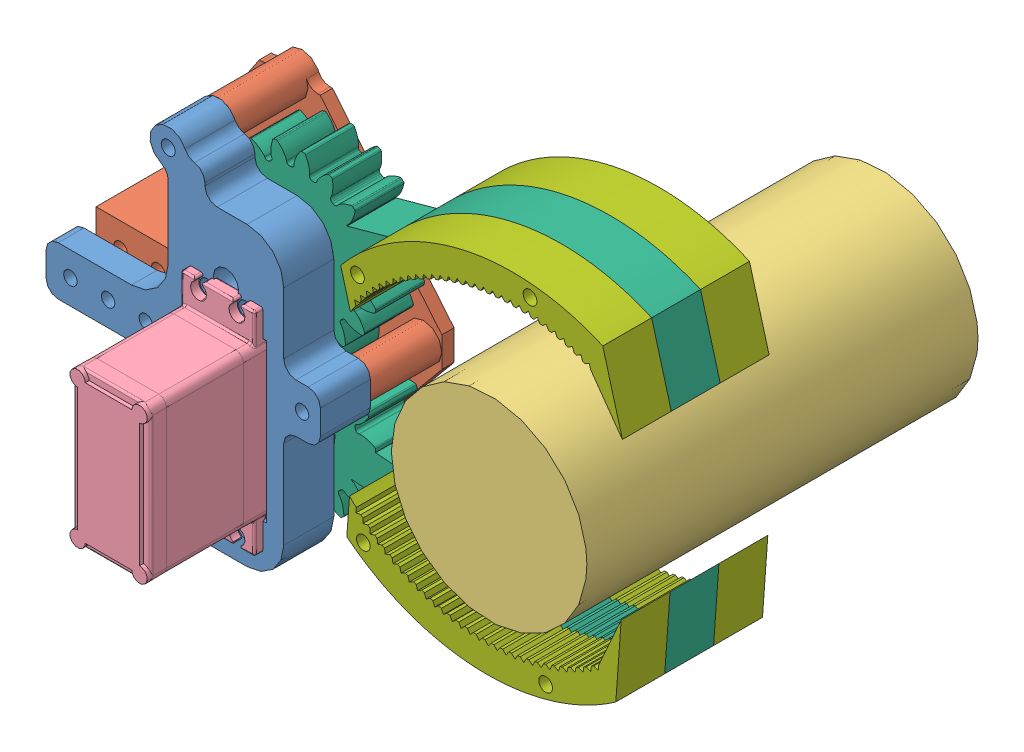
SolidWorks assembly GrippperAssembly, configuration Default. Lengths in mm.
Overall size (149.23 112.41 123.35).
11 component instances, 7 part files, 24 mates.
Components (placement in the parent):
- GripperRedesign-1: GripperRedesign [Default] at origin size (71.28 93.53 13)
- GripperRedesign2-1: GripperRedesign2 [Default] at (71.275 -35.654 -21.717) x (0 1 0) z (0 0 1) size (93.53 71.27 21.72)
- bottle-1: bottle [Default] at (123.8325 17.7435 -79.8506) size (50.8 50.8 101.6)
- Servo 20kg elbow and gripper2-1: Servo 20kg elbow and gripper2 [Default] at (46.75 -2.85 43.5) x (0 -1 0) z (1 0 0) size (55.1 45.65 20.12)
- horn-1: horn [Default] at (46.75 -12.8 -4.8) x (0.804878 -0.593441 0) z (0 0 1) size (21 21 5.5)
- Involute Spur Gear Generator - Better 0 3-13 EXTRA-3: Involute Spur Gear Generator - Better 0 3-13 EXTRA [Default] at (46.75 25.4 -18.034) x (-0.266205 0.963916 0) z (0 0 1) size (42.33 117.57 12.7)
- Involute Spur Gear Generator - Better 0 3-13 EXTRA-4: Involute Spur Gear Generator - Better 0 3-13 EXTRA [Default] at (46.75 -12.8 -4.8) x (-0.072019 -0.997403 0) z (0 0 -1) size (42.33 117.57 12.7)
- Involute Spur Gear Generator - Better 0 3-13 WIDER-3: Involute Spur Gear Generator - Better 0 3-13 WIDER [Default] at (46.75 25.4 -5.334) x (-0.266205 0.963916 0) z (0 0 1) size (32.24 69.85 12.7)
- Involute Spur Gear Generator - Better 0 3-13 WIDER-4: Involute Spur Gear Generator - Better 0 3-13 WIDER [Default] at (46.75 -12.8 7.9) x (-0.072019 -0.997403 0) z (0 0 -1) size (32.24 69.85 12.7)
- Involute Spur Gear Generator - Better 0 3-13 WIDER-5: Involute Spur Gear Generator - Better 0 3-13 WIDER [Default] at (46.75 25.4 -30.734) x (-0.266205 0.963916 0) z (0 0 1) size (32.24 69.85 12.7)
- Involute Spur Gear Generator - Better 0 3-13 WIDER-6: Involute Spur Gear Generator - Better 0 3-13 WIDER [Default] at (46.75 -12.8 -17.5) x (-0.072019 -0.997403 0) z (0 0 -1) size (32.24 69.85 12.7)
Mates (geometry in assembly coordinates):
- Coincident2: coincident anti-aligned: plane of GripperRedesign-1 through (0 0 0) normal (0 0 -1); plane of GripperRedesign2-1 through (66.5125 6.35 0) normal (0 0 1)
- Concentric4: concentric aligned: cylinder of GripperRedesign-1 through (66.5125 6.35 -15.875) axis (0 0 1) radius 1.778; cylinder of GripperRedesign2-1 through (66.5125 6.35 -21.717) axis (0 0 1) radius 1.8415
- Parallel5: parallel aligned: plane of GripperRedesign-1 through (71.275 0 -15.875) normal (1 0 0); plane of GripperRedesign2-1 through (71.275 -35.654 -18.542) normal (1 0 0)
- Coincident10: coincident anti-aligned: plane of GripperRedesign-1 through (0 0 3) normal (0 0 1); plane of Servo 20kg elbow and gripper2-1 through (46.75 -2.85 3) normal (0 0 -1)
- Concentric21: concentric anti-aligned: cylinder of GripperRedesign-1 through (51.75 22.2 0) axis (0 0 1) radius 1.778; cylinder of Servo 20kg elbow and gripper2-1 through (51.75 22.2 15.15) axis (0 0 -1) radius 2.075
- Concentric22: concentric anti-aligned: cylinder of GripperRedesign-1 through (41.75 22.2 0) axis (0 0 1) radius 1.778; cylinder of Servo 20kg elbow and gripper2-1 through (41.75 22.2 15.15) axis (0 0 -1) radius 2.075
- Concentric23: concentric aligned: cylinder of Servo 20kg elbow and gripper2-1 through (46.75 -12.8 -2.15) axis (0 0 1) radius 1; cylinder of horn-1 through (46.75 -12.8 -4.8) axis (0 0 1) radius 1.5
- Distance2: distance = 7.8 mm aligned: plane of horn-1 through (46.75 -12.8 -4.8) normal (0 0 -1); plane of Servo 20kg elbow and gripper2-1 through (46.75 -2.85 3) normal (0 0 -1)
- Distance3: distance = 5.334 mm anti-aligned: plane of Involute Spur Gear Generator - Better 0 3-13 EXTRA-3 through (46.75 25.4 -5.334) normal (0 0 1); plane of GripperRedesign-1 through (0 0 0) normal (0 0 -1)
- Concentric28: concentric anti-aligned: cylinder of GripperRedesign-1 through (46.75 25.4 13) axis (0 0 -1) radius 1.905; cylinder of Involute Spur Gear Generator - Better 0 3-13 EXTRA-3 through (46.75 25.4 -18.034) axis (0 0 1) radius 3.556
- Coincident12: coincident anti-aligned: plane of horn-1 through (46.75 -12.8 -4.8) normal (0 0 -1); plane of Involute Spur Gear Generator - Better 0 3-13 EXTRA-4 through (46.75 -12.8 -4.8) normal (0 0 1)
- Concentric29: concentric anti-aligned: cylinder of horn-1 through (46.75 -12.8 -4.8) axis (0 0 1) radius 1.5; cylinder of Involute Spur Gear Generator - Better 0 3-13 EXTRA-4 through (46.75 -12.8 -4.8) axis (0 0 -1) radius 3.556
- Coincident13: coincident anti-aligned: plane of Involute Spur Gear Generator - Better 0 3-13 EXTRA-3 through (46.75 25.4 -5.334) normal (0 0 1); plane of Involute Spur Gear Generator - Better 0 3-13 WIDER-3 through (46.75 25.4 -5.334) normal (0 0 -1)
- Concentric30: concentric aligned: cylinder of Involute Spur Gear Generator - Better 0 3-13 EXTRA-3 through (120.0913 56.0224 -106.934) axis (0 0 1) radius 1.778; cylinder of Involute Spur Gear Generator - Better 0 3-13 WIDER-3 through (120.0913 56.0224 -94.234) axis (0 0 1) radius 1.778
- Concentric31: concentric aligned: cylinder of Involute Spur Gear Generator - Better 0 3-13 EXTRA-3 through (75.273 38.6955 -106.934) axis (0 0 1) radius 1.778; cylinder of Involute Spur Gear Generator - Better 0 3-13 WIDER-3 through (75.273 38.6955 -94.234) axis (0 0 1) radius 1.778
- Coincident14: coincident anti-aligned: plane of Involute Spur Gear Generator - Better 0 3-13 EXTRA-4 through (46.75 -12.8 -4.8) normal (0 0 1); plane of Involute Spur Gear Generator - Better 0 3-13 WIDER-4 through (46.75 -12.8 -4.8) normal (0 0 -1)
- Concentric32: concentric aligned: cylinder of Involute Spur Gear Generator - Better 0 3-13 EXTRA-4 through (124.6722 -28.4461 84.1) axis (0 0 -1) radius 1.778; cylinder of Involute Spur Gear Generator - Better 0 3-13 WIDER-4 through (124.6722 -28.4461 96.8) axis (0 0 -1) radius 1.778
- Concentric33: concentric aligned: cylinder of Involute Spur Gear Generator - Better 0 3-13 EXTRA-4 through (77.3264 -20.2442 84.1) axis (0 0 -1) radius 1.778; cylinder of Involute Spur Gear Generator - Better 0 3-13 WIDER-4 through (77.3264 -20.2442 96.8) axis (0 0 -1) radius 1.778
- Concentric34: concentric aligned: cylinder of Involute Spur Gear Generator - Better 0 3-13 EXTRA-3 through (120.0913 56.0224 -106.934) axis (0 0 1) radius 1.778; cylinder of Involute Spur Gear Generator - Better 0 3-13 WIDER-5 through (120.0913 56.0224 -119.634) axis (0 0 1) radius 1.778
- Concentric35: concentric aligned: cylinder of Involute Spur Gear Generator - Better 0 3-13 EXTRA-3 through (75.273 38.6955 -106.934) axis (0 0 1) radius 1.778; cylinder of Involute Spur Gear Generator - Better 0 3-13 WIDER-5 through (75.273 38.6955 -119.634) axis (0 0 1) radius 1.778
- Coincident15: coincident anti-aligned: plane of Involute Spur Gear Generator - Better 0 3-13 EXTRA-3 through (46.75 25.4 -18.034) normal (0 0 -1); plane of Involute Spur Gear Generator - Better 0 3-13 WIDER-5 through (46.75 25.4 -18.034) normal (0 0 1)
- Concentric36: concentric aligned: cylinder of Involute Spur Gear Generator - Better 0 3-13 EXTRA-4 through (77.3264 -20.2442 84.1) axis (0 0 -1) radius 1.778; cylinder of Involute Spur Gear Generator - Better 0 3-13 WIDER-6 through (77.3264 -20.2442 71.4) axis (0 0 -1) radius 1.778
- Concentric37: concentric aligned: cylinder of Involute Spur Gear Generator - Better 0 3-13 EXTRA-4 through (124.6722 -28.4461 84.1) axis (0 0 -1) radius 1.778; cylinder of Involute Spur Gear Generator - Better 0 3-13 WIDER-6 through (124.6722 -28.4461 71.4) axis (0 0 -1) radius 1.778
- Coincident16: coincident anti-aligned: plane of Involute Spur Gear Generator - Better 0 3-13 EXTRA-4 through (46.75 -12.8 -17.5) normal (0 0 -1); plane of Involute Spur Gear Generator - Better 0 3-13 WIDER-6 through (46.75 -12.8 -17.5) normal (0 0 1)
